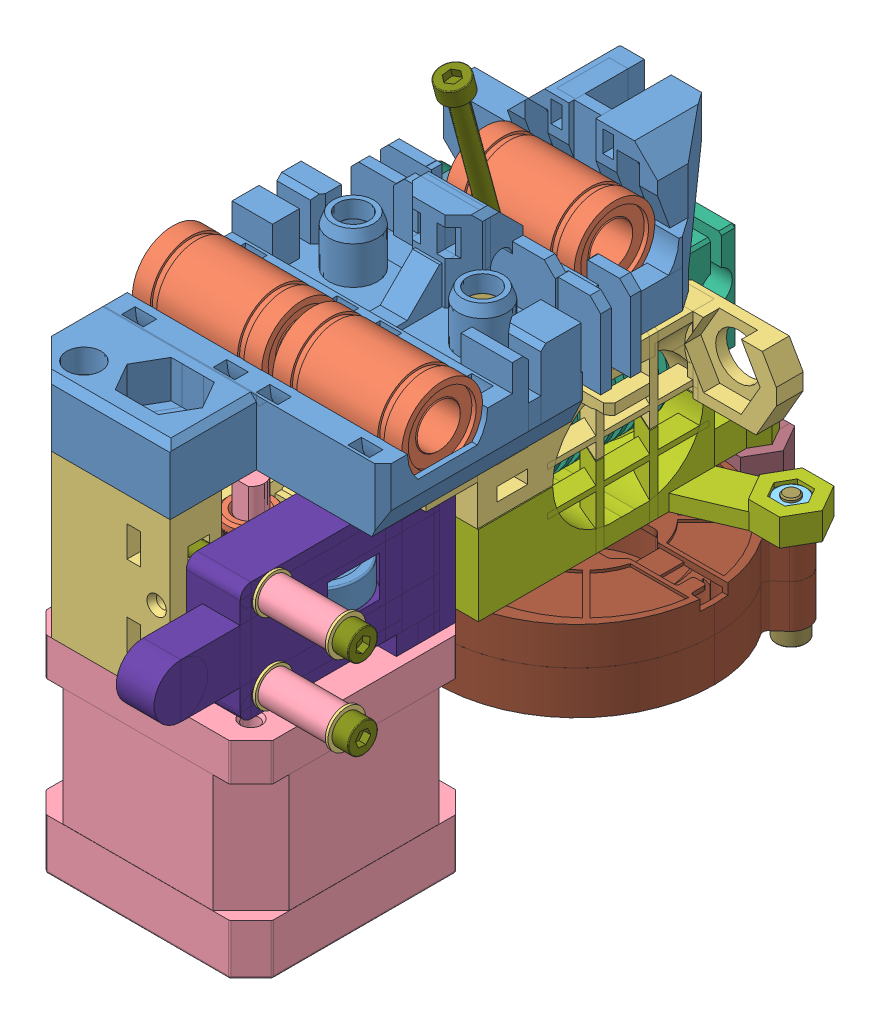
SolidWorks assembly Assembly x-carriage, configuration Valor predeterminado. Lengths in mm.
Overall size (67.39 111.94 121.32).
46 component instances, 22 part files, 110 mates.
Components (placement in the parent):
- x-carriage-1: x-carriage [Valor predeterminado] at (-16.5 0 20) x (-1 0 0) z (0 1 0) size (56 93 25)
- Linear bearing LM8UU-1: Linear bearing LM8UU [Valor predeterminado] at (18.5556 22.2452 59.3251) size (24 15 15)
- Linear bearing LM8UU-2: Linear bearing LM8UU [Valor predeterminado] at (5.5556 22.3192 25.5393) x (1 0 0) z (0 -0.840652 0.541576) size (24 15 15)
- Linear bearing LM8UU-3: Linear bearing LM8UU [Valor predeterminado] at (-7.4444 22.2452 59.3251) size (24 15 15)
- extruder-body-1: extruder-body [Valor predeterminado] at (17.5 0 51) x (-1 0 0) z (0 -1 0) size (60.5 87 30)
- Stepper motor Nema 17-1: Stepper motor Nema 17 [Valor predeterminado] at (-27.6278 -42.5 76.2544) x (0 -1 0) z (0 0 -1) size (62.01 42.01 48.01)
- Nut DIN 934 - M3-1: Nut DIN 934 - M3 [Valor predeterminado] at (12 -5.2 44.5) x (0 1 0) z (0.5 0 0.866025) size (2.4 5.5 6.35)
- Nut DIN 934 - M3-2: Nut DIN 934 - M3 [Valor predeterminado] at (12 -11.3 44.5) x (0 1 0) z (0.5 0 0.866025) size (2.4 5.5 6.35)
- Nut DIN 934 - M3-3: Nut DIN 934 - M3 [Valor predeterminado] at (-23 -4.79 46.5) x (0 1 0) z (0.965926 0 -0.258819) size (2.4 5.5 6.35)
- Nut DIN 934 - M3-4: Nut DIN 934 - M3 [Valor predeterminado] at (-12 -12.2 44.5) x (0 1 0) z (0.866025 0 0.5) size (2.4 5.5 6.35)
- Hotend E3D V6-1: Hotend E3D V6 [Valor predeterminado] at (-50 -15 8.3) x (0 1 0) z (0 0 1) size (26.65 22.3 62.82)
- extruder-cover-1: extruder-cover [Valor predeterminado] at (17.5 0 51) x (-1 0 0) z (0 -1 0) size (64.05 60.8 14.8)
- Nut DIN 934 - M3-5: Nut DIN 934 - M3 [Valor predeterminado] at (-12 -26.81 44.5) x (0 -1 0) z (0 0 1) size (2.4 5.5 6.35)
- Nut DIN 934 - M3-6: Nut DIN 934 - M3 [Valor predeterminado] at (30.75 -26.81 6) x (0 -1 0) z (-0.5 0 0.866025) size (2.4 5.5 6.35)
- Screw DIN 912 - M3 x 18 --- 18N-1: Screw DIN 912 - M3 x 18 --- 18N [Valor predeterminado] at (12 -30 44.5) x (0 -1 0) z (-0.995479 0 0.094979) size (21 5.5 5.5)
- Screw DIN 912 - M3 x 25 --- 18N-1: Screw DIN 912 - M3 x 25 --- 18N [Valor predeterminado] at (-23 -30 46.5) x (0 -1 0) z (-0.658305 0 0.752751) size (28 5.5 5.5)
- Screw DIN 912 - M3 x 30 --- 18N-1: Screw DIN 912 - M3 x 30 --- 18N [Valor predeterminado] at (-19 -0.5 56.5) x (0 1 0) z (0.848686 0 0.528897) size (33 5.5 5.5)
- Screw DIN 912 - M3 x 30 --- 18N-2: Screw DIN 912 - M3 x 30 --- 18N [Valor predeterminado] at (12 -0.5 56.5) x (0 1 0) z (-0.021186 0 0.999776) size (33 5.5 5.5)
- Nut DIN 934 - M3-7: Nut DIN 934 - M3 [Valor predeterminado] at (-4.2 -7.5 87.7) x (-1 0 0) z (0 -0.866025 0.5) size (2.4 5.5 6.35)
- Nut DIN 934 - M3-8: Nut DIN 934 - M3 [Valor predeterminado] at (-4.2 -22.5 87.7) x (-1 0 0) z (0 0.866025 -0.5) size (2.4 5.5 6.35)
- Radial flow fan - 50 x 15-1: Radial flow fan - 50 x 15 [Valor predeterminado] at (10.75 -30 24) x (1 0 0) z (0 0 -1) size (51.3 15 51.07)
- Screw DIN 912 - M3 x 20 --- 20N-1: Screw DIN 912 - M3 x 20 --- 20N [Valor predeterminado] at (30.75 -48 6) x (0 -1 0) z (0.184115 0 0.982905) size (23 5.5 5.5)
- Screw DIN 912 - M3 x 20 --- 20N-2: Screw DIN 912 - M3 x 20 --- 20N [Valor predeterminado] at (-12 -48 44.5) x (0 -1 0) z (-0.302592 0 0.95312) size (23 5.5 5.5)
- fan-nozzle-1: fan-nozzle [Valor predeterminado] at (-17.5 -30 -10) x (1 0 0) z (0 -1 0) size (38.8 10.05 23)
- Screw DIN 912 - M3 x 20 --- 20N-3: Screw DIN 912 - M3 x 20 --- 20N [Valor predeterminado] at (12.5 -46.5 -5) x (0 -1 0) z (0.184115 0 0.982905) size (23 5.5 5.5)
- Axil flow fan - 30 x 30 x 10-1: Axil flow fan - 30 x 30 x 10 [Valor predeterminado] at (-27.84 -15 23) x (0 0 -1) z (1 0 0) size (30 30 10.44)
- Screw DIN 912 - M3 x 16 --- 16N-1: Screw DIN 912 - M3 x 16 --- 16N [Valor predeterminado] at (-30.84 -3 11) x (-1 0 0) z (0 0.925018 0.379924) size (19 5.5 5.5)
- Screw DIN 912 - M3 x 16 --- 16N-2: Screw DIN 912 - M3 x 16 --- 16N [Valor predeterminado] at (-30.84 -27 35) x (-1 0 0) z (0 0.925018 0.379924) size (19 5.5 5.5)
- Screw DIN 912 - M3 x 16 --- 16N-3: Screw DIN 912 - M3 x 16 --- 16N [Valor predeterminado] at (-30.84 -3 35) x (-1 0 0) z (0 0.925018 0.379924) size (19 5.5 5.5)
- Screw DIN 912 - M3 x 16 --- 16N-4: Screw DIN 912 - M3 x 16 --- 16N [Valor predeterminado] at (-30.84 -27 11) x (-1 0 0) z (0 0.925018 0.379924) size (19 5.5 5.5)
- Screw DIN 912 - M3 x 40 --- 18N-1: Screw DIN 912 - M3 x 40 --- 18N [Valor predeterminado] at (-19 8 87.5) x (0 1 0) z (0.582907 0 -0.812539) size (43 5.5 5.5)
- Screw DIN 912 - M3 x 30 --- 18N-3: Screw DIN 912 - M3 x 30 --- 18N [Valor predeterminado] at (-12 15 44.5) x (0 1 0) z (0.989582 0 -0.143972) size (33 5.5 5.5)
- Screw DIN 912 - M3 x 40 --- 18N-2: Screw DIN 912 - M3 x 40 --- 18N [Valor predeterminado] at (0 42.5348 38.1292) x (0 0.965926 0.258819) z (0.799471 -0.155474 0.580236) size (43 5.5 5.5)
- Screw DIN 912 - M3 x 20 --- 20N-4: Screw DIN 912 - M3 x 20 --- 20N [Valor predeterminado] at (12 15 44.5) x (0 1 0) z (-0.485958 0 -0.873982) size (23 5.5 5.5)
- extruder-idler-1: extruder-idler [Valor predeterminado] at (16 -15 52.5) x (0 -1 0) z (-1 0 0) size (25.5 57 10)
- idler-shaft-1: idler-shaft [Valor predeterminado] at (9 -7 72.5) x (0.425613 0 -0.904905) z (0 -1 0) size (5 5 16)
- Radial ball bearing DIN 625 - 625-1: Radial ball bearing DIN 625 - 625 [Valor predeterminado] at (9 -15 72.5) x (0 1 0) z (0.991606 0 -0.1293) size (5 16 16)
- Screw DIN 912 - M3 x 40 --- 18N-3: Screw DIN 912 - M3 x 40 --- 18N [Valor predeterminado] at (33 -22.5 87.7) x (1 0 0) z (0 -0.798126 0.602491) size (43 5.5 5.5)
- Screw DIN 912 - M3 x 40 --- 18N-4: Screw DIN 912 - M3 x 40 --- 18N [Valor predeterminado] at (33 -7.5 87.7) x (1 0 0) z (0 0.48262 -0.87583) size (43 5.5 5.5)
- Filament drive gear MK8 - 9 x 11-1: Filament drive gear MK8 - 9 x 11 [Valor predeterminado] at (-3.5 -22.65 72) size (9 11 9.5)
- Washer DIN 125A - M3-1: Washer DIN 125A - M3 [Valor predeterminado] at (29.5 -22.5 87.7) size (0.5 7 7)
- Washer DIN 125A - M3-2: Washer DIN 125A - M3 [Valor predeterminado] at (29.5 -7.5 87.7) size (0.5 7 7)
- Extruder spring-1: Extruder spring [Valor predeterminado] at (29.5 -7.5 87.7) x (0 -0.615763 0.787931) z (-1 0 0) size (6 6 13)
- Extruder spring-2: Extruder spring [Valor predeterminado] at (29.5 -22.5 87.7) x (0 -0.615763 0.787931) z (-1 0 0) size (6 6 13)
- Washer DIN 125A - M3-3: Washer DIN 125A - M3 [Valor predeterminado] at (16 -7.5 87.7) size (0.5 7 7)
- Washer DIN 125A - M3-4: Washer DIN 125A - M3 [Valor predeterminado] at (16 -22.5 87.7) size (0.5 7 7)
Mates (geometry in assembly coordinates):
- Coincidente3: coincident: plane of assembly through (0 0 0) normal (0 0 1); plane of x-carriage-1 through (-2.5 3 0) normal (0 0 -1); plane of assembly
- Coincidente4: coincident: plane of assembly through (0 0 0) normal (0 1 0); plane of x-carriage-1 through (-29 0 53) normal (0 -1 0); plane of assembly
- Simétrico2: symmetric: plane of assembly; plane of assembly; plane of x-carriage-1 through (-26 -1 39) normal (-1 0 0); plane of x-carriage-1 through (26 -1 39) normal (1 0 0); plane of assembly
- Concêntrico1: concentric: cylinder of assembly; cylinder of assembly; cylinder of x-carriage-1 through (30 12 65) axis (-1 0 0) radius 7.45; cylinder of Linear bearing LM8UU-1 through (13 12 65) axis (1 0 0) radius 7.5
- Concêntrico2: concentric: cylinder of assembly; cylinder of assembly; cylinder of x-carriage-1 through (30 12 65) axis (-1 0 0) radius 7.45; cylinder of Linear bearing LM8UU-3 through (-13 12 65) axis (1 0 0) radius 7.5
- Coincidente6: coincident: plane of assembly; plane of assembly; plane of x-carriage-1 through (-25 -1 53) normal (1 0 0); plane of Linear bearing LM8UU-3 through (-25 4.6307 63.6057) normal (-1 0 0)
- Coincidente7: coincident: plane of assembly; plane of assembly; plane of x-carriage-1 through (25 -1 53) normal (-1 0 0); plane of Linear bearing LM8UU-1 through (25 5.8098 63.8288) normal (1 0 0)
- Concêntrico3: concentric: cylinder of assembly; cylinder of assembly; cylinder of x-carriage-1 through (17.5 12 20) axis (-1 0 0) radius 7.45; cylinder of Linear bearing LM8UU-2 through (0 12 20) axis (1 0 0) radius 7.5
- Coincidente8: coincident: plane of assembly through (0 0 0) normal (1 0 0); plane of Linear bearing LM8UU-2 through (0 22.3192 25.5393) normal (-1 0 0); plane of assembly
- Concêntrico4: concentric: cylinder of x-carriage-1 through (-19 -50 87.5) axis (0 1 0) radius 1.8; cylinder of ? through (-19 -4 87.5) axis (0 -1 0) radius 1.65
- Coincidente11: coincident: plane of x-carriage-1 through (2.5 0 93) normal (0 0 1); plane of ? through (-24.5 0 93) normal (0 0 1)
- Concêntrico5: concentric: cylinder of ? through (-19 -4 87.5) axis (0 -1 0) radius 1.65; cylinder of Stepper motor Nema 17-1 through (-19 -33.5 87.5) axis (0 1 0) radius 1.5
- Coincidente13: coincident: plane of ? through (-24.5 -30 93) normal (0 -1 0); plane of Stepper motor Nema 17-1 through (-3.5 -30 72) normal (0 1 0)
- Coincidente14: coincident: plane of ? through (-24.5 0 93) normal (0 0 1); plane of Stepper motor Nema 17-1 through (17.5 -37 93) normal (0 0 1)
- Concêntrico6: concentric: cylinder of ? through (12 0.01 44.5) axis (0 -1 0) radius 1.65; cylinder of Nut DIN 934 - M3-1 through (12 -4 44.5) axis (0 -1 0) radius 1.25
- Paralelo3: parallel: plane of ? through (18.5 -4 47.35) normal (0 0 -1); plane of Nut DIN 934 - M3-1 through (13.5877 -4 41.75) normal (0 0 -1)
- Coincidente16: coincident: plane of ? through (18.5 -4 47.35) normal (0 -1 0); plane of Nut DIN 934 - M3-1 through (13.5877 -4 41.75) normal (0 1 0)
- Concêntrico7: concentric: cylinder of ? through (12 -12.7 44.5) axis (0 -1 0) radius 1.65; cylinder of Nut DIN 934 - M3-2 through (12 -10.1 44.5) axis (0 -1 0) radius 1.25
- Paralelo4: parallel: plane of ? through (18.5 -10 47.35) normal (0 0 -1); plane of Nut DIN 934 - M3-2 through (13.5877 -10.1 41.75) normal (0 0 -1)
- Coincidente18: coincident: plane of ? through (18.5 -12.5 47.35) normal (0 1 0); plane of Nut DIN 934 - M3-2 through (13.5877 -12.5 41.75) normal (0 -1 0)
- Paralelo5: parallel: plane of ? through (-20.7373 0.01 48.7627) normal (-0.258819 0 -0.965926); plane of Nut DIN 934 - M3-3 through (-22.1781 -3.59 43.4328) normal (-0.258819 0 -0.965926)
- Concêntrico8: concentric: cylinder of ? through (-23 -6.2 46.5) axis (0 -1 0) radius 1.7; cylinder of Nut DIN 934 - M3-3 through (-23 -3.59 46.5) axis (0 -1 0) radius 1.25
- Coincidente20: coincident: plane of ? through (-23 -5.99 46.5) normal (0 1 0); plane of Nut DIN 934 - M3-3 through (-25.2454 -5.99 44.2546) normal (0 -1 0)
- Concêntrico9: concentric: cylinder of ? through (-12 0.01 44.5) axis (0 -1 0) radius 1.65; cylinder of Nut DIN 934 - M3-4 through (-12 -11 44.5) axis (0 -1 0) radius 1.25
- Paralelo6: parallel: line of ? through (-14.7713 -11 46.1) axis (0 0 -1); plane of Nut DIN 934 - M3-4 through (-9.25 -11 46.0877) normal (1 0 0)
- Coincidente22: coincident: plane of ? through (-12 -11 44.5) normal (0 -1 0); plane of Nut DIN 934 - M3-4 through (-12 -11 41.3246) normal (0 1 0)
- Concêntrico10: concentric: cylinder of ? through (0 -15 51) axis (0 0 -1) radius 7.13; cylinder of Hotend E3D V6-1 through (0 -15 44.3) axis (0 0 -1) radius 6
- Coincidente23: coincident: plane of ? through (-24.5 0 51) normal (0 0 -1); plane of Hotend E3D V6-1 through (-8 -15 51) normal (0 0 1)
- Concêntrico11: concentric: cylinder of ? through (-12 0.01 44.5) axis (0 -1 0) radius 1.65; cylinder of Nut DIN 934 - M3-5 through (-12 -28.01 44.5) axis (0 1 0) radius 1.25
- Paralelo8: parallel: line of ? through (-12 -28.01 41.3) axis (0.866025 0 0.5); plane of Nut DIN 934 - M3-5 through (-12 -28.01 47.6754) normal (-0.5 0 0.866025)
- Coincidente26: coincident: plane of ? through (-12 -28.01 44.5) normal (0 1 0); plane of Nut DIN 934 - M3-5 through (-14.75 -28.01 42.9123) normal (0 -1 0)
- Concêntrico12: concentric: cylinder of ? through (30.75 -15 6) axis (0 -1 0) radius 1.65; cylinder of Nut DIN 934 - M3-6 through (30.75 -28.01 6) axis (0 1 0) radius 1.25
- Paralelo9: parallel: line of ? through (29.15 -28.01 3.2287) axis (1 0 0); plane of Nut DIN 934 - M3-6 through (32.3377 -28.01 8.75) normal (0 0 1)
- Coincidente28: coincident: plane of ? through (30.75 -28.01 6) normal (0 1 0); plane of Nut DIN 934 - M3-6 through (29.1623 -28.01 3.25) normal (0 -1 0)
- Concêntrico13: concentric: cylinder of Hotend E3D V6-1 through (0 -15 44.3) axis (0 0 -1) radius 6; cylinder of ? through (0 -15 51) axis (0 0 -1) radius 6.13
- Concêntrico14: concentric: cylinder of ? through (-23 -6.2 46.5) axis (0 -1 0) radius 1.7; cylinder of ? through (-23 -6.2 46.5) axis (0 -1 0) radius 1.7
- Paralelo10: parallel: plane of ? through (-17.5 0 51) normal (-1 0 0); plane of Hotend E3D V6-1 through (-8 -9.5 -1.0677) normal (-1 0 0)
- Concêntrico15: concentric: cylinder of ? through (-23 -27 46.5) axis (0 -1 0) radius 3.1; cylinder of Screw DIN 912 - M3 x 25 --- 18N-1 through (-23 -30 46.5) axis (0 -1 0) radius 2.75
- Coincidente30: coincident: plane of ? through (-23 -27 46.5) normal (0 -1 0); plane of Screw DIN 912 - M3 x 25 --- 18N-1 through (-20.9299 -27 48.3103) normal (0 1 0)
- Concêntrico16: concentric: cylinder of ? through (12 -27 44.5) axis (0 -1 0) radius 3.1; cylinder of Screw DIN 912 - M3 x 18 --- 18N-1 through (12 -30 44.5) axis (0 -1 0) radius 1.5
- Coincidente31: coincident: plane of ? through (12 -27 44.5) normal (0 -1 0); plane of Screw DIN 912 - M3 x 18 --- 18N-1 through (12.2612 -27 47.2376) normal (0 1 0)
- Concêntrico19: concentric: cylinder of ? through (-19 1 56.5) axis (0 -1 0) radius 3.1; cylinder of Screw DIN 912 - M3 x 30 --- 18N-1 through (-19 -0.5 56.5) axis (0 1 0) radius 2.75
- Coincidente33: coincident: plane of ? through (-19 -3.5 56.5) normal (0 1 0); plane of Screw DIN 912 - M3 x 30 --- 18N-1 through (-20.4545 -3.5 58.8339) normal (0 -1 0)
- Concêntrico20: concentric: cylinder of ? through (12 1 56.5) axis (0 -1 0) radius 3.1; cylinder of Screw DIN 912 - M3 x 30 --- 18N-2 through (12 -0.5 56.5) axis (0 1 0) radius 2.75
- Coincidente34: coincident: plane of ? through (12 -3.5 56.5) normal (0 1 0); plane of Screw DIN 912 - M3 x 30 --- 18N-2 through (9.2506 -3.5 56.4417) normal (0 -1 0)
- Coincidente37: coincident: plane of ? through (17.5 0 87.7) normal (0 0 1); line of Nut DIN 934 - M3-7 through (-5.4 -7.5 87.7) axis (1 0 0)
- Coincidente36: coincident: plane of ? through (17.5 -7.5 51) normal (0 1 0); line of Nut DIN 934 - M3-7 through (-5.4 -7.5 87.7) axis (1 0 0)
- Paralelo12: parallel: plane of ? through (-5.5 -10.35 104.5) normal (0 1 0); plane of Nut DIN 934 - M3-7 through (-5.4 -4.75 89.2877) normal (0 1 0)
- Coincidente39: coincident: plane of ? through (-3 -4.65 104.5) normal (-1 0 0); plane of Nut DIN 934 - M3-7 through (-3 -4.75 89.2877) normal (1 0 0)
- Coincidente40: coincident: plane of ? through (17.5 -22.5 51) normal (0 -1 0); line of Nut DIN 934 - M3-8 through (-5.4 -22.5 87.7) axis (1 0 0)
- Coincidente41: coincident: plane of ? through (17.5 0 87.7) normal (0 0 1); line of Nut DIN 934 - M3-8 through (-5.4 -22.5 87.7) axis (1 0 0)
- Paralelo13: parallel: plane of Nut DIN 934 - M3-8 through (-5.4 -19.75 89.2877) normal (0 1 0); plane of ? through (-5.5 -25.35 104.5) normal (0 1 0)
- Coincidente43: coincident: plane of ? through (-3 -19.65 104.5) normal (-1 0 0); plane of Nut DIN 934 - M3-8 through (-3 -25.25 86.1123) normal (1 0 0)
- Concêntrico21: concentric: cylinder of ? through (30.75 -15 6) axis (0 -1 0) radius 1.65; cylinder of Radial flow fan - 50 x 15-1 through (30.75 -37 6) axis (0 -1 0) radius 2.25
- Paralelo14: parallel: plane of ? through (-17.5 -15 51) normal (-1 0 0); plane of Radial flow fan - 50 x 15-1 through (-16.75 -37 -1.4) normal (-1 0 0)
- Coincidente45: coincident: plane of ? through (17.5 -30 51) normal (0 -1 0); plane of Radial flow fan - 50 x 15-1 through (-12.25 -30 44) normal (0 1 0)
- Concêntrico22: concentric: cylinder of assembly; cylinder of assembly; cylinder of Nut DIN 934 - M3-6 through (30.75 -28.01 6) axis (0 1 0) radius 1.25; cylinder of Screw DIN 912 - M3 x 20 --- 20N-1 through (30.75 -48 6) axis (0 -1 0) radius 1.5
- Coincidente46: coincident: plane of assembly; plane of assembly; plane of Radial flow fan - 50 x 15-1 through (-12.25 -45 44) normal (0 -1 0); plane of Screw DIN 912 - M3 x 20 --- 20N-1 through (33.453 -45 5.4937) normal (0 1 0)
- Concêntrico23: concentric: cylinder of assembly; cylinder of assembly; cylinder of Nut DIN 934 - M3-5 through (-12 -28.01 44.5) axis (0 1 0) radius 1.25; cylinder of Screw DIN 912 - M3 x 20 --- 20N-2 through (-12 -48 44.5) axis (0 -1 0) radius 1.5
- Coincidente47: coincident: plane of assembly; plane of assembly; plane of Radial flow fan - 50 x 15-1 through (-12.25 -45 44) normal (0 -1 0); plane of Screw DIN 912 - M3 x 20 --- 20N-2 through (-9.3789 -45 45.3321) normal (0 1 0)
- Concêntrico24: concentric: cylinder of ? through (12.5 -20 -5) axis (0 -1 0) radius 1.5; cylinder of fan-nozzle-1 through (12.5 -20 -5) axis (0 -1 0) radius 1.6
- Coincidente48: coincident: plane of ? through (12.5 -30 -5) normal (0 -1 0); plane of fan-nozzle-1 through (-17.5 -30 -10) normal (0 1 0)
- Coincidente49: coincident: plane of ? through (-16.5 -23 -5) normal (0 0 1); plane of fan-nozzle-1 through (-22.5 -23 -5) normal (0 0 -1)
- Concêntrico25: concentric: cylinder of assembly; cylinder of assembly; cylinder of fan-nozzle-1 through (12.5 -20 -5) axis (0 -1 0) radius 1.6; cylinder of Screw DIN 912 - M3 x 20 --- 20N-3 through (12.5 -46.5 -5) axis (0 -1 0) radius 1.5
- Coincidente50: coincident: plane of assembly; plane of assembly; plane of fan-nozzle-1 through (12.5 -43.5 -5) normal (0 -1 0); plane of Screw DIN 912 - M3 x 20 --- 20N-3 through (15.203 -43.5 -5.5063) normal (0 1 0)
- Concêntrico26: concentric: cylinder of ? through (-17.501 -3 11) axis (1 0 0) radius 1.5; cylinder of Axil flow fan - 30 x 30 x 10-1 through (-27.84 -3 11) axis (1 0 0) radius 1.7
- Coincidente51: coincident: plane of ? through (17.5 0 51) normal (0 1 0); plane of Axil flow fan - 30 x 30 x 10-1 through (-27.84 0 8) normal (0 1 0)
- Coincidente52: coincident: plane of ? through (-17.5 0 51) normal (-1 0 0); plane of Axil flow fan - 30 x 30 x 10-1 through (-17.5 -15 23) normal (1 0 0)
- Concêntrico27: concentric: cylinder of assembly; cylinder of assembly; cylinder of Axil flow fan - 30 x 30 x 10-1 through (-27.84 -3 11) axis (1 0 0) radius 1.7; cylinder of Screw DIN 912 - M3 x 16 --- 16N-1 through (-30.84 -3 11) axis (-1 0 0) radius 1.5
- Coincidente53: coincident: plane of assembly; plane of assembly; plane of Axil flow fan - 30 x 30 x 10-1 through (-27.84 -15 23) normal (-1 0 0); plane of Screw DIN 912 - M3 x 16 --- 16N-1 through (-27.84 -4.0448 13.5438) normal (1 0 0)
- Concêntrico28: concentric: cylinder of assembly; cylinder of assembly; cylinder of Axil flow fan - 30 x 30 x 10-1 through (-27.84 -27 11) axis (1 0 0) radius 1.7; cylinder of Screw DIN 912 - M3 x 16 --- 16N-4 through (-30.84 -27 11) axis (-1 0 0) radius 1.5
- Concêntrico29: concentric: cylinder of assembly; cylinder of assembly; cylinder of Axil flow fan - 30 x 30 x 10-1 through (-27.84 -27 35) axis (1 0 0) radius 1.7; cylinder of Screw DIN 912 - M3 x 16 --- 16N-2 through (-30.84 -27 35) axis (-1 0 0) radius 1.5
- Concêntrico30: concentric: cylinder of assembly; cylinder of assembly; cylinder of Axil flow fan - 30 x 30 x 10-1 through (-27.84 -3 35) axis (1 0 0) radius 1.7; cylinder of Screw DIN 912 - M3 x 16 --- 16N-3 through (-30.84 -3 35) axis (-1 0 0) radius 1.5
- Coincidente54: coincident: plane of assembly; plane of assembly; plane of Axil flow fan - 30 x 30 x 10-1 through (-27.84 -15 23) normal (-1 0 0); plane of Screw DIN 912 - M3 x 16 --- 16N-4 through (-27.84 -28.0448 13.5438) normal (1 0 0)
- Coincidente55: coincident: plane of assembly; plane of assembly; plane of Axil flow fan - 30 x 30 x 10-1 through (-27.84 -15 23) normal (-1 0 0); plane of Screw DIN 912 - M3 x 16 --- 16N-3 through (-27.84 -4.0448 37.5438) normal (1 0 0)
- Coincidente56: coincident: plane of assembly; plane of assembly; plane of Axil flow fan - 30 x 30 x 10-1 through (-27.84 -15 23) normal (-1 0 0); plane of Screw DIN 912 - M3 x 16 --- 16N-2 through (-27.84 -28.0448 37.5438) normal (1 0 0)
- Coincidente57: coincident: plane of x-carriage-1 through (-29 0 53) normal (0 -1 0); plane of ? through (-24.5 0 93) normal (0 1 0)
- Concêntrico31: concentric: cylinder of assembly; cylinder of assembly; cylinder of x-carriage-1 through (-19 5 87.5) axis (0 1 0) radius 3.2; cylinder of Screw DIN 912 - M3 x 40 --- 18N-1 through (-19 8 87.5) axis (0 1 0) radius 2.75
- Coincidente58: coincident: plane of assembly; plane of assembly; plane of x-carriage-1 through (-19 5 87.5) normal (0 1 0); plane of Screw DIN 912 - M3 x 40 --- 18N-1 through (-16.7655 5 89.103) normal (0 -1 0)
- Concêntrico32: concentric: cylinder of assembly; cylinder of assembly; cylinder of x-carriage-1 through (-12 -1 44.5) axis (0 1 0) radius 1.8; cylinder of Screw DIN 912 - M3 x 30 --- 18N-3 through (-12 15 44.5) axis (0 1 0) radius 1.5
- Coincidente59: coincident: plane of assembly; plane of assembly; plane of x-carriage-1 through (-12 12 44.5) normal (0 1 0); plane of Screw DIN 912 - M3 x 30 --- 18N-3 through (-11.6041 12 47.2213) normal (0 -1 0)
- Concêntrico34: concentric: cylinder of assembly; cylinder of assembly; cylinder of x-carriage-1 through (0 1 27) axis (0 0.965926 0.258819) radius 1.52; cylinder of Screw DIN 912 - M3 x 40 --- 18N-2 through (0 42.5348 38.1292) axis (0 0.965926 0.258819) radius 1.5
- Coincidente61: coincident: plane of assembly; plane of assembly; plane of x-carriage-1 through (0 1 27) normal (0 0.965926 0.258819); plane of Screw DIN 912 - M3 x 40 --- 18N-2 through (-0.9011 0.6896 28.1583) normal (0 -0.965926 -0.258819)
- Concêntrico35: concentric: cylinder of assembly; cylinder of assembly; cylinder of x-carriage-1 through (12 -1 44.5) axis (0 1 0) radius 1.8; cylinder of Screw DIN 912 - M3 x 20 --- 20N-4 through (12 15 44.5) axis (0 1 0) radius 1.5
- Coincidente62: coincident: plane of assembly; plane of assembly; plane of x-carriage-1 through (12 12 44.5) normal (0 1 0); plane of Screw DIN 912 - M3 x 20 --- 20N-4 through (14.4035 12 43.1636) normal (0 -1 0)
- Concêntrico36: concentric: cylinder of assembly; cylinder of assembly; cylinder of Screw DIN 912 - M3 x 30 --- 18N-2 through (12 -0.5 56.5) axis (0 1 0) radius 1.5; cylinder of extruder-idler-1 through (12 0 56.5) axis (0 -1 0) radius 1.7
- Simétrico3: symmetric: plane of ? through (5.3 -7.5 92) normal (0 -1 0); plane of Stepper motor Nema 17-1 through (-3.5 -30 72) normal (0 1 0); plane of extruder-idler-1 through (16 -18.75 52.5) normal (0 1 0)
- Concêntrico37: concentric: cylinder of assembly; cylinder of assembly; cylinder of extruder-idler-1 through (9 -6.5 72.5) axis (0 -1 0) radius 2.5; cylinder of idler-shaft-1 through (9 -8 72.5) axis (0 -1 0) radius 2.5
- Coincidente63: coincident: plane of assembly; plane of assembly; plane of extruder-idler-1 through (16 -15 52.5) normal (0 -1 0); plane of idler-shaft-1 through (9 -15 72.5) normal (0 -1 0)
- Concêntrico38: concentric: cylinder of assembly; cylinder of assembly; cylinder of idler-shaft-1 through (9 -8 72.5) axis (0 -1 0) radius 2.5; cylinder of Radial ball bearing DIN 625 - 625-1 through (9 -35.6375 72.5) axis (0 1 0) radius 2.5
- Coincidente64: coincident: plane of assembly; plane of assembly; plane of extruder-idler-1 through (16 -15 52.5) normal (0 -1 0); plane of Radial ball bearing DIN 625 - 625-1 through (9 -15 72.5) normal (0 1 0)
- Concêntrico39: concentric: cylinder of assembly; cylinder of assembly; cylinder of Nut DIN 934 - M3-7 through (-5.4 -7.5 87.7) axis (1 0 0) radius 1.25; cylinder of Screw DIN 912 - M3 x 40 --- 18N-4 through (33 -7.5 87.7) axis (1 0 0) radius 1.5
- Concêntrico40: concentric: cylinder of assembly; cylinder of assembly; cylinder of Nut DIN 934 - M3-8 through (-5.4 -22.5 87.7) axis (1 0 0) radius 1.25; cylinder of Screw DIN 912 - M3 x 40 --- 18N-3 through (33 -22.5 87.7) axis (1 0 0) radius 1.5
- Concêntrico41: concentric: cylinder of assembly; cylinder of assembly; cylinder of Stepper motor Nema 17-1 through (-3.5 -34.4 72) axis (0 -1 0) radius 2.5; cylinder of Filament drive gear MK8 - 9 x 11-1 through (-3.5 -12.15 72) axis (0 1 0) radius 2.5
- Coincidente65: coincident: line of ? through (0 -15 68) axis (0 0 -1); plane of Filament drive gear MK8 - 9 x 11-1 through (-3.5 -15 72) normal (0 1 0)
- Concêntrico42: concentric: cylinder of assembly; cylinder of assembly; cylinder of Screw DIN 912 - M3 x 40 --- 18N-3 through (33 -22.5 87.7) axis (1 0 0) radius 1.5; cylinder of Washer DIN 125A - M3-1 through (30 -22.5 87.7) axis (-1 0 0) radius 1.6
- Coincidente66: coincident: plane of assembly; plane of assembly; plane of Screw DIN 912 - M3 x 40 --- 18N-3 through (30 -20.8432 89.8948) normal (-1 0 0); plane of Washer DIN 125A - M3-1 through (30 -22.5 87.7) normal (1 0 0)
- Concêntrico43: concentric: cylinder of assembly; cylinder of assembly; cylinder of Screw DIN 912 - M3 x 40 --- 18N-4 through (33 -7.5 87.7) axis (1 0 0) radius 1.5; cylinder of Washer DIN 125A - M3-2 through (30 -7.5 87.7) axis (-1 0 0) radius 1.6
- Coincidente67: coincident: plane of assembly; plane of assembly; plane of Screw DIN 912 - M3 x 40 --- 18N-4 through (30 -9.9085 86.3728) normal (-1 0 0); plane of Washer DIN 125A - M3-2 through (30 -7.5 87.7) normal (1 0 0)
- Paralelo15: parallel: plane of assembly; plane of assembly; plane of x-carriage-1 through (2.5 0 76.8) normal (1 0 0); plane of extruder-idler-1 through (16 -4 63.5) normal (1 0 0)
- Concêntrico44: concentric: cylinder of assembly; cylinder of assembly; cylinder of Screw DIN 912 - M3 x 40 --- 18N-3 through (33 -22.5 87.7) axis (1 0 0) radius 1.5; cylinder of Extruder spring-2 through (16.5 -22.5 87.7) axis (1 0 0) radius 2.1
- Concêntrico45: concentric: cylinder of assembly; cylinder of assembly; cylinder of Screw DIN 912 - M3 x 40 --- 18N-4 through (33 -7.5 87.7) axis (1 0 0) radius 1.5; cylinder of Extruder spring-1 through (16.5 -7.5 87.7) axis (1 0 0) radius 2.1
- Coincidente69: coincident: plane of assembly; plane of assembly; plane of Washer DIN 125A - M3-2 through (29.5 -7.5 87.7) normal (-1 0 0); plane of Extruder spring-1 through (29.5 -7.5 87.7) normal (1 0 0)
- Coincidente70: coincident: plane of assembly; plane of assembly; plane of Washer DIN 125A - M3-1 through (29.5 -22.5 87.7) normal (-1 0 0); plane of Extruder spring-2 through (29.5 -22.5 87.7) normal (1 0 0)
- Concêntrico46: concentric: cylinder of assembly; cylinder of assembly; cylinder of Screw DIN 912 - M3 x 40 --- 18N-3 through (33 -22.5 87.7) axis (1 0 0) radius 1.5; cylinder of Washer DIN 125A - M3-4 through (16.5 -22.5 87.7) axis (-1 0 0) radius 1.6
- Coincidente71: coincident: plane of assembly; plane of assembly; plane of Extruder spring-2 through (16.5 -22.5 87.7) normal (-1 0 0); plane of Washer DIN 125A - M3-4 through (16.5 -22.5 87.7) normal (1 0 0)
- Coincidente72: coincident: plane of assembly; plane of assembly; plane of Extruder spring-1 through (16.5 -7.5 87.7) normal (-1 0 0); plane of Washer DIN 125A - M3-3 through (16.5 -7.5 87.7) normal (1 0 0)
- Concêntrico47: concentric: cylinder of assembly; cylinder of assembly; cylinder of Screw DIN 912 - M3 x 40 --- 18N-4 through (33 -7.5 87.7) axis (1 0 0) radius 1.5; cylinder of Washer DIN 125A - M3-3 through (16.5 -7.5 87.7) axis (-1 0 0) radius 1.6
- Coincidente73: coincident: plane of assembly; plane of assembly; plane of extruder-idler-1 through (16 -4 63.5) normal (1 0 0); plane of Washer DIN 125A - M3-3 through (16 -7.5 87.7) normal (-1 0 0)
- Coincidente74: coincident: plane of assembly; plane of assembly; plane of extruder-idler-1 through (16 -4 63.5) normal (1 0 0); plane of Washer DIN 125A - M3-4 through (16 -22.5 87.7) normal (-1 0 0)
